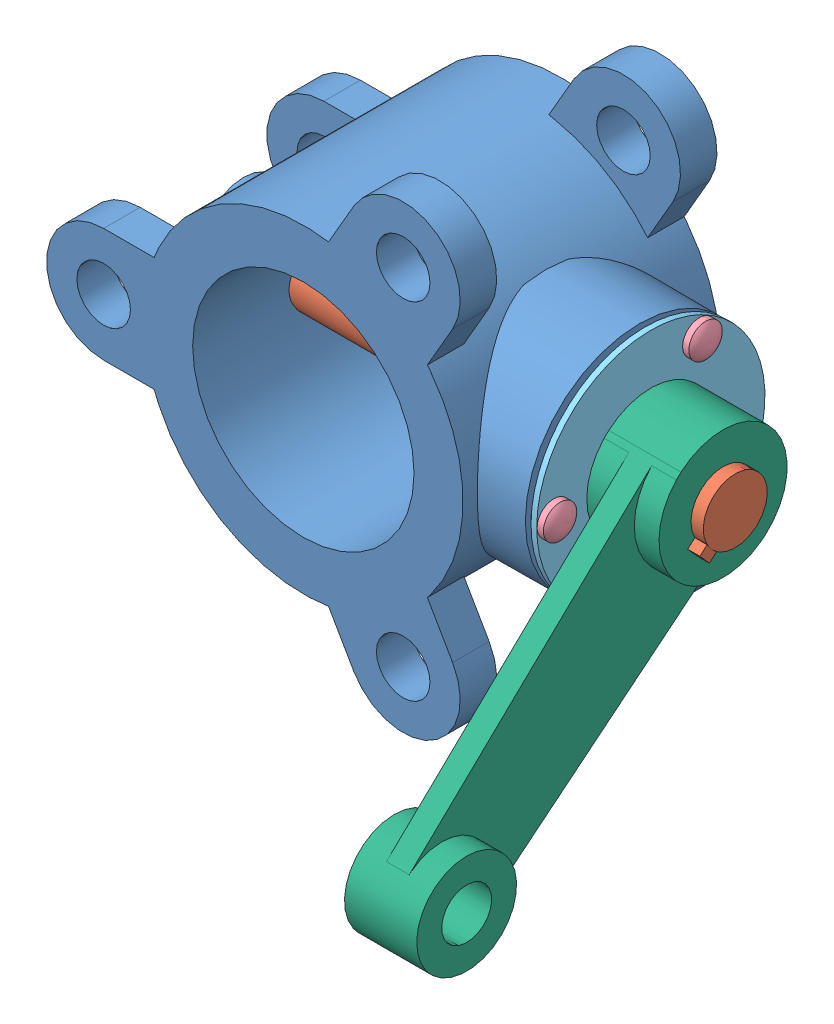
SolidWorks assembly Assem2, configuration Default. Lengths in mm.
Overall size (491 469.37 432.94).
10 component instances, 6 part files, 21 mates.
Components (placement in the parent):
- Part1-1: Part1 [Default] at (137.3189 193.0985 232.0682) size (407 403.11 225)
- Part5-1: Part5 [Default] at (369.3189 193.0985 344.5682) x (0 -0.74893 -0.66265) z (1 0 0) size (100 100 424)
- Part3-1: Part3 [Default] at (137.3189 196.4117 340.8236) x (1 0 0) z (0 -0.66265 0.74893) size (192 192 5)
- Part7-1: Part7 [Default] at (97.3189 206.3515 329.5896) x (0.997534 -0.052562 -0.046507) z (0.070183 0.747083 0.661016) size (29.24 30.13 29.24)
- Part7-2: Part7 [Default] at (177.3189 206.3515 329.5896) x (1 0 0) z (0 0.74893 0.66265) size (29.24 30.13 29.24)
- Part4-2: Part4 [Default] at (329.3189 193.0985 344.5682) x (0 -0.5 0.866025) z (-1 0 0) size (200 200 5)
- Part2-4: Part2 [Default] at (392.6189 193.0985 344.5682) x (0 -0.655782 0.75495) z (-1 0 0) size (399.9 112.3 63.3)
- Part7-3: Part7 [Default] at (339.3189 266.7107 302.0682) x (0 -1 0) z (0 0 1) size (29.24 30.13 29.24)
- Part7-4: Part7 [Default] at (339.3189 119.4863 302.0682) x (0 -1 0) z (0 0 1) size (29.24 30.13 29.24)
- Part7-5: Part7 [Default] at (339.3189 193.0985 429.5682) x (0 -1 0) z (0 0 1) size (29.24 30.13 29.24)
Mates (geometry in assembly coordinates):
- Coincident1: coincident aligned: axis of Part1-1 through (277.3187 193.0985 344.5682) axis (1 0 0); axis of Part5-1 through (40.3189 193.0985 344.5682) axis (1 0 0)
- Coincident2: coincident anti-aligned: plane of Part1-1 through (294.3189 193.0985 344.5682) normal (1 0 0); plane of Part5-1 through (294.3189 193.0985 344.5682) normal (-1 0 0)
- Coincident3: coincident anti-aligned: axis of Part5-1 through (97.3189 183.462 347.2401) axis (0 0.963645 -0.267184); axis of Part3-1 through (97.3189 197.9167 343.2323) axis (0 -0.963645 0.267184)
- Coincident4: coincident anti-aligned: axis of Part5-1 through (177.3189 183.462 347.2401) axis (0 0.963645 -0.267184); axis of Part3-1 through (177.3189 197.9167 343.2323) axis (0 -0.963645 0.267184)
- Coincident5: coincident anti-aligned: plane of Part5-1 through (234.3189 233.1761 489.115) normal (0 0.963645 -0.267184); plane of Part3-1 through (137.3189 193.0985 344.5682) normal (0 -0.963645 0.267184)
- Coincident6: coincident aligned: axis of Part5-1 through (97.3189 183.462 347.2401) axis (0 0.963645 -0.267184); axis of Part7-1 through (97.3189 183.462 347.2401) axis (0 0.963645 -0.267184)
- Coincident7: coincident anti-aligned: plane of Part5-1 through (97.3189 183.462 347.2401) normal (0 0.963645 -0.267184); plane of Part7-1 through (97.3189 183.462 347.2401) normal (0 -0.963645 0.267184)
- Coincident8: coincident anti-aligned: plane of Part5-1 through (177.3189 183.462 347.2401) normal (0 0.963645 -0.267184); plane of Part7-2 through (177.3189 183.462 347.2401) normal (0 -0.963645 0.267184)
- Coincident9: coincident aligned: axis of Part5-1 through (177.3189 183.462 347.2401) axis (0 0.963645 -0.267184); axis of Part7-2 through (177.3189 183.462 347.2401) axis (0 0.963645 -0.267184)
- Coincident17: coincident anti-aligned: axis of Part5-1 through (403.3189 193.0985 344.5682) axis (-1 0 0); axis of Part4-2 through (324.3189 193.0985 344.5682) axis (1 0 0)
- Coincident18: coincident anti-aligned: axis of Part1-1 through (277.3189 193.0985 429.5682) axis (1 0 0); axis of Part4-2 through (329.3189 193.0985 429.5682) axis (-1 0 0)
- Coincident19: coincident anti-aligned: plane of Part5-1 through (324.3189 193.0985 344.5682) normal (1 0 0); plane of Part4-2 through (324.3189 193.0985 344.5682) normal (-1 0 0)
- Coincident20: coincident anti-aligned: axis of Part5-1 through (403.3189 193.0985 344.5682) axis (-1 0 0); axis of Part2-4 through (370.9689 193.0985 344.5682) axis (1 0 0)
- Coincident21: coincident anti-aligned: plane of Part4-2 through (329.3189 193.0985 344.5682) normal (1 0 0); plane of Part2-4 through (329.3189 193.0985 344.5682) normal (-1 0 0)
- Coincident22: coincident anti-aligned: plane of Part5-1; plane of Part2-4
- Coincident23: coincident aligned: axis of Part1-1 through (277.3189 266.7107 302.0682) axis (1 0 0); axis of Part7-3 through (309.3189 266.7107 302.0682) axis (1 0 0)
- Coincident24: coincident anti-aligned: plane of Part4-2 through (329.3189 193.0985 344.5682) normal (1 0 0); plane of Part7-3 through (329.3189 256.5607 302.0682) normal (-1 0 0)
- Coincident25: coincident aligned: axis of Part1-1 through (277.3189 119.4863 302.0682) axis (1 0 0); axis of Part7-4 through (309.3189 119.4863 302.0682) axis (1 0 0)
- Coincident26: coincident anti-aligned: plane of Part4-2 through (329.3189 193.0985 344.5682) normal (1 0 0); plane of Part7-4 through (329.3189 109.3363 302.0682) normal (-1 0 0)
- Coincident28: coincident aligned: axis of Part1-1 through (277.3189 193.0985 429.5682) axis (1 0 0); axis of Part7-5 through (309.3189 193.0985 429.5682) axis (1 0 0)
- Coincident29: coincident anti-aligned: plane of Part4-2 through (329.3189 193.0985 344.5682) normal (1 0 0); plane of Part7-5 through (329.3189 182.9485 429.5682) normal (-1 0 0)
